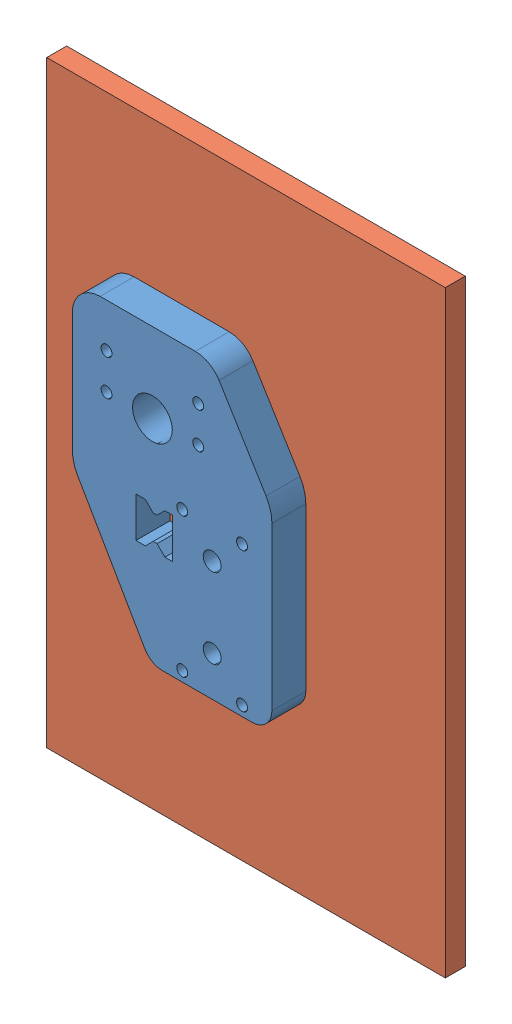
SolidWorks assembly 3, configuration Default. Lengths in mm.
Overall size (200 300 27).
3 component instances, 2 part files, 6 mates.
Components (placement in the parent):
- Y Screw Support motor top end left2-2: Y Screw Support motor top end left2 [Default] at (210 -390.3941 8) size (100.2 147 19)
- platform-1: platform [Default] at origin size (200 300 10)
- Y Screw Support motor top end left2-1: Y Screw Support motor top end left2 [Default] at (-10 -390.3941 46) x (-1 0 0) z (0 0 -1) size (100.2 147 19) (hidden)
Mates (geometry in assembly coordinates):
- Coincident7: coincident anti-aligned: plane of Y Screw Support motor top end left2-2; line of platform-1 through (32.4795 143.11 8) axis (0.5 -0.866025 0)
- Concentric3: concentric: cylinder of Y Screw Support motor top end left2-2 through (100 139.6059 -11) axis (0 0 -1) radius 4.5; cylinder of platform-1 through (100 139.6059 0) axis (0 0 1) radius 4.45
- Concentric4: concentric: cylinder of Y Screw Support motor top end left2-2 through (100 99.6059 -11) axis (0 0 -1) radius 4.5; cylinder of platform-1 through (100 99.6059 0) axis (0 0 1) radius 4.45
- Coincident13: coincident: plane of platform-1 through (108.464 212.6059 8) normal (0 0 1); plane of Y Screw Support motor top end left2-2 through (117 82.6059 8) normal (0 0 -1)
- Concentric5: concentric anti-aligned: cylinder of Y Screw Support motor top end left2-2 through (100 139.6059 27) axis (0 0 1) radius 4.5; cylinder of Y Screw Support motor top end left2-1 through (100 139.6059 27) axis (0 0 -1) radius 4.5
- Concentric6: concentric anti-aligned: cylinder of Y Screw Support motor top end left2-2 through (100 99.6059 27) axis (0 0 1) radius 4.5; cylinder of Y Screw Support motor top end left2-1 through (100 99.6059 27) axis (0 0 -1) radius 4.5
